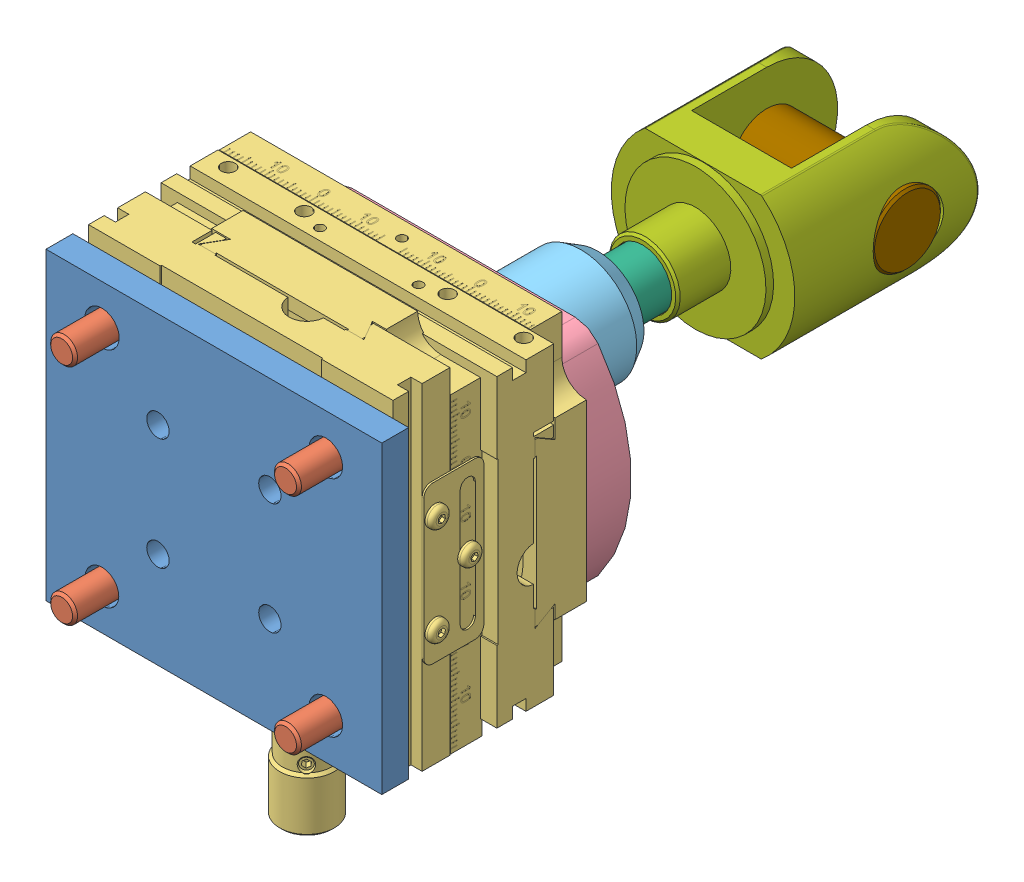
SolidWorks assembly Camera Post, configuration Default. Lengths in mm.
Overall size (98.3 98.25 159.76).
16 component instances, 9 part files, 36 mates.
Components (placement in the parent):
- Base altura câmara-1: Base altura câmara [Default] at (-25.0412 0.9003 65.6472) size (75 68 6)
- socket head cap screw_iso_12-1: socket head cap screw_iso_12 [ISO 4762 M6 x 20 - 20N] at (-12.5412 9.9003 54.6472) x (0 0 1) z (-0.613808 -0.789456 0) size (26 10 10)
- socket head cap screw_iso_12-2: socket head cap screw_iso_12 [ISO 4762 M6 x 20 - 20N] at (-12.5412 59.9003 54.6472) x (0 0 1) z (-0.468301 -0.883569 0) size (26 10 10)
- socket head cap screw_iso_12-3: socket head cap screw_iso_12 [ISO 4762 M6 x 20 - 20N] at (37.4588 59.9003 54.6472) x (0 0 1) z (-0.701703 -0.712469 0) size (26 10 10)
- socket head cap screw_iso_12-4: socket head cap screw_iso_12 [ISO 4762 M6 x 20 - 20N] at (37.4588 9.9003 54.6472) x (0 0 1) z (-0.710367 -0.703832 0) size (26 10 10)
- DTS25_M-Solidworks (1)-1: DTS25_M-Solidworks (1) [Default] at (-25.0412 -24.4808 73.3972) x (-1 0 0) z (0 0 1) size (69.9 98.25 20)
- DTS25_M-Solidworks (1)-2: DTS25_M-Solidworks (1) [Default] at (-46.9223 72.4003 53.6972) x (0 1 0) z (0 0 1) size (69.9 98.25 20)
- BA3_M-Solidworks-1: BA3_M-Solidworks [Default] at (12.5088 34.1567 20.9472) x (-1 0 0) z (0 -1 0) size (75 10 50)
- socket head cap screw_iso_12-5: socket head cap screw_iso_12 [ISO 4762 M6 x 16 - 16N] at (37.4588 34.9003 9.9472) x (0 0 1) z (-0.387084 -0.922044 0) size (22 10 10)
- socket head cap screw_iso_12-6: socket head cap screw_iso_12 [ISO 4762 M6 x 16 - 16N] at (-12.5412 34.9003 9.9472) x (0 0 1) z (-0.386644 -0.922229 0) size (22 10 10)
- socket head cap screw_iso_12-7: socket head cap screw_iso_12 [ISO 4762 M6 x 16 - 16N] at (12.5088 34.1567 25.0892) x (0 0 -1) z (-0.84234 -0.538946 0) size (22 10 10)
- PH30_M-Solidworks-1: PH30_M-Solidworks [Default] at (13.8995 29.3922 6.5019) x (-1 0 0) z (0 -1 0) size (25 30.44 33)
- TR50_M-Solidworks-1: TR50_M-Solidworks [Default] at (12.5088 34.1567 5.9472) x (0.965492 0.260434 0) z (-0.260434 0.965492 0) size (12.67 55.03 12.87)
- Forquilha da camara-1: Forquilha da camara [Default] at (12.5088 34.1567 -37.5528) x (0 1 0) z (0 0 1) size (33.29 41.75 55.06)
- slotted set screw flat point_iso_13-2: slotted set screw flat point_iso_13 [ISO 4766 - M4 x 6-N] at (12.5088 18.3067 -41.5528) x (0 1 0) z (-0.585816 0 0.810444) size (6 4 4)
- Eixo suporte-1: Eixo suporte [Default] at (32.8088 34.1567 -62.9028) x (0 0.823026 -0.568004) z (0 0.568004 0.823026) size (15.7 40.8 15.7)
Mates (geometry in assembly coordinates):
- Coincident1: coincident anti-aligned: plane of Base altura câmara-1 through (-25.0412 0.9003 65.6472) normal (0 0 -1); plane of DTS25_M-Solidworks (1)-1 through (46.4588 -2.5997 65.6472) normal (0 0 1)
- Concentric4: concentric anti-aligned: circle of Base altura câmara-1; circle of DTS25_M-Solidworks (1)-1
- Concentric5: concentric anti-aligned: circle of Base altura câmara-1; circle of DTS25_M-Solidworks (1)-1
- Concentric6: concentric aligned: cylinder of Base altura câmara-1 through (-12.5412 9.9003 71.6472) axis (0 0 -1) radius 3.75; cylinder of socket head cap screw_iso-1 through (-12.5412 9.9003 22.8972) axis (0 0 -1) radius 3
- Concentric7: concentric aligned: cylinder of Base altura câmara-1 through (-12.5412 59.9003 71.6472) axis (0 0 -1) radius 3.85; cylinder of socket head cap screw_iso-2 through (-12.5412 59.9003 22.8972) axis (0 0 -1) radius 3
- Concentric8: concentric aligned: cylinder of Base altura câmara-1 through (37.4588 59.9003 71.6472) axis (0 0 -1) radius 3.75; cylinder of socket head cap screw_iso-3 through (37.4588 59.9003 22.8972) axis (0 0 -1) radius 3
- Concentric9: concentric aligned: cylinder of Base altura câmara-1 through (37.4588 9.9003 71.6472) axis (0 0 -1) radius 3.75; cylinder of socket head cap screw_iso-4 through (37.4588 9.9003 22.8972) axis (0 0 -1) radius 3
- Coincident3: coincident aligned: plane of socket head cap screw_iso-1 through (-16.4885 12.9694 60.6472) normal (0 0 1); plane of socket head cap screw_iso-4 through (33.9396 13.4522 60.6472) normal (0 0 1)
- Coincident6: coincident anti-aligned: plane of socket head cap screw_iso-1 through (-16.4885 12.9694 60.6472) normal (0 0 1); circle of DTS25_M-Solidworks (1)-1
- Coincident7: coincident aligned: plane of socket head cap screw_iso-2 through (-14.702 61.0456 80.6472) normal (0 0 1); plane of socket head cap screw_iso-3 through (35.7165 61.6163 80.6472) normal (0 0 1)
- Coincident8: coincident aligned: plane of socket head cap screw_iso-1 through (-14.4718 11.4014 80.6472) normal (0 0 1); plane of socket head cap screw_iso-2 through (-14.702 61.0456 80.6472) normal (0 0 1)
- Concentric10: concentric aligned: cylinder of BA3_M-Solidworks-1 through (12.5088 34.1567 25.9472) axis (0 0 1) radius 3.3655; cylinder of socket head cap screw_iso-7 through (12.5088 34.1567 56.8392) axis (0 0 1) radius 3
- Coincident11: coincident anti-aligned: plane of BA3_M-Solidworks-1 through (9.1433 34.1567 19.0892) normal (0 0 1); plane of socket head cap screw_iso-7 through (15.2035 29.945 19.0892) normal (0 0 -1)
- Concentric11: concentric aligned: cylinder of socket head cap screw_iso-7 through (12.5088 34.1567 56.8392) axis (0 0 1) radius 3; cylinder of PH30_M-Solidworks-1 through (12.5088 34.1567 15.0582) axis (0 0 1) radius 2.5
- Coincident12: coincident anti-aligned: plane of BA3_M-Solidworks-1 through (37.4635 52.8003 15.9472) normal (0 0 -1); plane of PH30_M-Solidworks-1 through (40.1502 34.1567 15.9472) normal (0 0 1)
- Parallel5: parallel aligned: plane of BA3_M-Solidworks-1 through (37.454 9.1503 15.9472) normal (0 -1 0); plane of PH30_M-Solidworks-1 through (8.7394 13.7827 -5.9248) normal (0 -1 0)
- Concentric12: concentric anti-aligned: cylinder of PH30_M-Solidworks-1 through (12.5088 34.1567 -14.0528) axis (0 0 1) radius 12.5; cylinder of TR50_M-Solidworks-1 through (12.5088 34.1567 -44.0654) axis (0 0 -1) radius 6.3373
- Distance1: distance = 10 mm anti-aligned: plane of BA3_M-Solidworks-1 through (37.4635 52.8003 15.9472) normal (0 0 -1); plane of TR50_M-Solidworks-1 through (18.1369 35.6749 5.9472) normal (0 0 1)
- Concentric14: concentric aligned: cylinder of TR50_M-Solidworks-1 through (12.5088 34.1567 -44.0654) axis (0 0 -1) radius 6.3373; cylinder of Forquilha da camara-1 through (12.5088 34.1567 -24.0528) axis (0 0 -1) radius 7.9
- Parallel6: parallel aligned: plane of BA3_M-Solidworks-1 through (37.454 9.1503 15.9472) normal (0 -1 0); plane of Forquilha da camara-1 through (-0.4923 18.3067 -11.1382) normal (0 -1 0)
- Distance2: distance = 10 mm anti-aligned: plane of Forquilha da camara-1 through (12.5088 34.1567 -24.0528) normal (0 0 1); plane of PH30_M-Solidworks-1 through (40.1502 34.1567 -14.0528) normal (0 0 -1)
- Coincident17: coincident aligned: plane of Forquilha da camara-1 through (-0.4923 18.3067 -11.1382) normal (0 -1 0); plane of slotted set screw flat point_iso-2 through (12.5088 18.3067 -41.5528) normal (0 -1 0)
- Concentric15: concentric aligned: circle of Forquilha da camara-1; circle of slotted set screw flat point_iso-2
- Concentric16: concentric anti-aligned: cylinder of Forquilha da camara-1 through (33.1088 34.1567 -62.9028) axis (-1 0 0) radius 7.85; cylinder of Eixo suporte-1 through (-7.9912 34.1567 -62.9028) axis (1 0 0) radius 7.85
- Tangent5: tangent aligned: cylinder of Forquilha da camara-1 through (12.5088 34.1567 -78.7528) axis (0 0 1) radius 20.5; plane of Eixo suporte-1 through (-7.9912 34.1567 -62.9028) normal (-1 0 0)
- Coincident18: coincident anti-aligned: plane of DTS25_M-Solidworks (1)-2 through (-25.0412 68.7503 25.9472) normal (0 0 -1); plane of BA3_M-Solidworks-1 through (37.4635 52.8003 25.9472) normal (0 0 1)
- Parallel7: parallel aligned: plane of DTS25_M-Solidworks (1)-2 through (-3.0412 0.5003 28.0472) normal (0 -1 0); plane of BA3_M-Solidworks-1 through (37.454 9.1503 15.9472) normal (0 -1 0)
- Distance3: distance = 8.1 mm aligned: plane of DTS25_M-Solidworks (1)-2 through (-25.0412 1.0503 25.9472) normal (0 -1 0); plane of BA3_M-Solidworks-1 through (37.454 9.1503 15.9472) normal (0 -1 0)
- Distance4: distance = 48.6 mm aligned: plane of Forquilha da camara-1 through (1.3588 89.5042 -78.7528) normal (1 0 0); plane of DTS25_M-Solidworks (1)-2 through (49.9588 16.2543 37.4472) normal (1 0 0)
- Concentric17: concentric aligned: cylinder of DTS25_M-Solidworks (1)-2 through (-12.5412 34.9003 25.9472) axis (0 0 -1) radius 2.5; cylinder of socket head cap screw_iso-6 through (-12.5412 34.9003 -21.8028) axis (0 0 -1) radius 3
- Concentric18: concentric aligned: cylinder of DTS25_M-Solidworks (1)-2 through (37.4588 34.9003 25.9472) axis (0 0 -1) radius 2.5; cylinder of socket head cap screw_iso-5 through (37.4588 34.9003 -21.8028) axis (0 0 -1) radius 3
- Coincident22: coincident anti-aligned: plane of BA3_M-Solidworks-1 through (37.4635 52.8003 15.9472) normal (0 0 -1); plane of socket head cap screw_iso-5 through (32.8486 36.8357 15.9472) normal (0 0 1)
- Coincident23: coincident anti-aligned: plane of BA3_M-Solidworks-1 through (37.4635 52.8003 15.9472) normal (0 0 -1); plane of socket head cap screw_iso-6 through (-17.1523 36.8335 15.9472) normal (0 0 1)
- Coincident24: coincident anti-aligned: circle of DTS25_M-Solidworks (1)-1; circle of DTS25_M-Solidworks (1)-2
- Parallel8: parallel aligned: plane of DTS25_M-Solidworks (1)-1 through (-21.5412 -2.5997 52.9472) normal (-1 0 0); plane of DTS25_M-Solidworks (1)-2 through (-25.0412 19.9003 33.2472) normal (-1 0 0)
- Parallel9: parallel aligned: plane of DTS25_M-Solidworks (1)-1 through (27.4588 72.4003 52.9472) normal (0 1 0); plane of DTS25_M-Solidworks (1)-2 through (-25.0412 68.9003 33.2472) normal (0 1 0)
